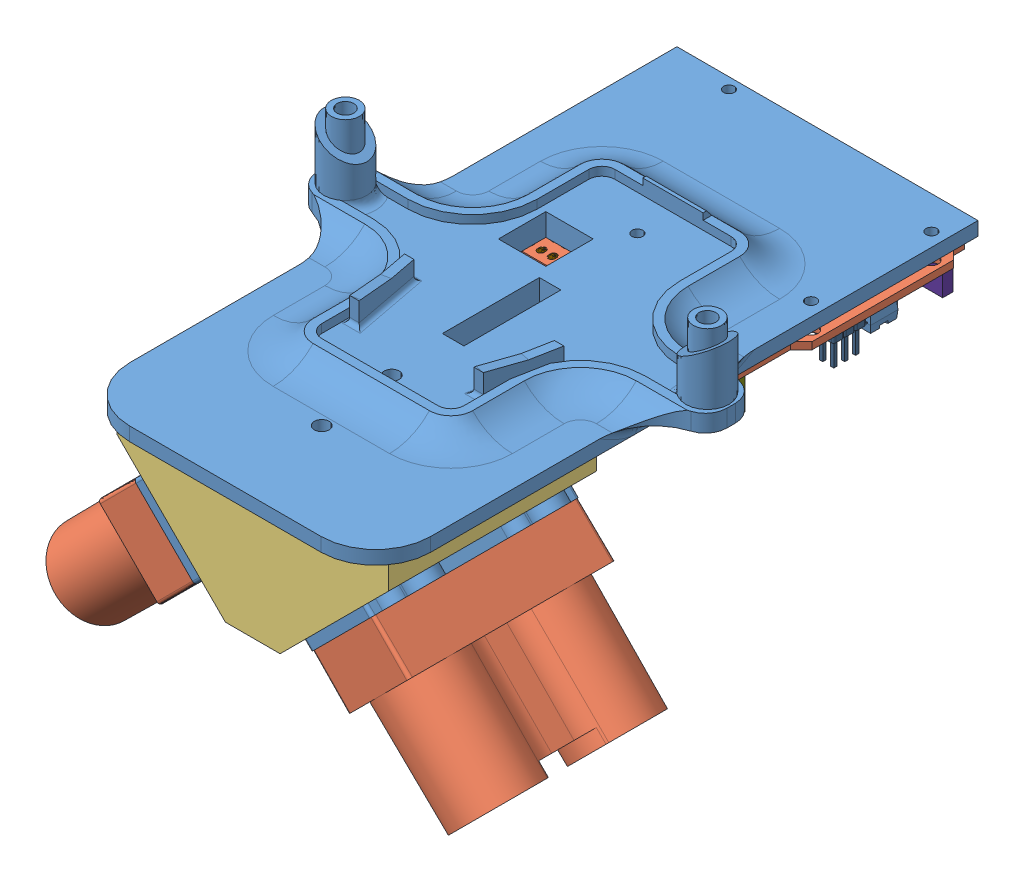
SolidWorks assembly Iris_LiDAR_Arduino_Mount, configuration Default. Lengths in mm.
Overall size (118.99 81.67 139.7).
94 component instances, 39 part files, 10 mates.
Components (placement in the parent):
- Iris_LiDAR_MountingPlate-1: Iris_LiDAR_MountingPlate [Default] x (1 0 0) z (0 1 0) size (95 139.7 22.9)
- arduino uno-1: arduino uno [Default] at (-34.29 -16.8811 -69.85) x (0 0 -1) z (-1 0 0) size (53.34 15.25 74.93)
  - unoboard blue-1: unoboard blue [Default] at origin size (53.34 1.65 68.58)
  - 47uf CAP Dcase-1: 47uf CAP Dcase [Default] at (-9.4141 0 -18.4991) x (0 0 -1) z (1 0 0) size (6.6 5.81 8)
  - USB SHELL-1: USB SHELL [Default] at (-38.02 0.43 6.35) size (13.72 15.2 16.51)
  - USB core-1: USB core [Default] at (-38.02 0.43 6.35) size (11.3 10.68 15.75)
  - usb top contact-1: usb top contact [Default] at (-36.77 6.52 5.97) size (1 9.67 13.76)
  - usb btm contact-1: usb btm contact [Default] at (-36.77 4.84 5.97) size (1 6.84 11.76)
  - usb btm contact-2: usb btm contact [Default] at (-39.27 4.84 5.97) size (1 6.84 11.76)
  - usb top contact-2: usb top contact [Default] at (-39.27 6.52 5.97) size (1 9.67 13.76)
  - power jack-1: power jack [Default] at (-7.675 0 1.905) size (11.2 15.2 15.9)
  - 47uf CAP Dcase-2: 47uf CAP Dcase [Default] at (-9.4141 0 -25.7132) x (0 0 -1) z (1 0 0) size (6.6 5.81 8)
  - crystal-1: crystal [Default] at (-26.162 0 -18.923) x (1 0 0) z (0 0 -1) size (4 5 11)
  - 2pin_header__02-1: 2pin_header__02 [Default] at (-46.23 0 -15.75) size (5 11.75 2.54)
  - nano - reg-1: nano - reg [Default] at (-17.399 0 -7.747) size (6.5 1.69 8.3)
  - led-1: led [Default] at (-34.29 0 -27.94) x (0 0 1) z (-1 0 0) size (4 0.9 1.55)
  - 2pin_header__02-2: 2pin_header__02 [Default] at (-30.43 0 -64.91) x (0 0 1) z (-1 0 0) size (5 11.75 2.54)
  - dip28-1: dip28 [Default] at (-16.383 1.5 -46.355) x (0 0 -1) z (1 0 0) size (35.48 2.8 10.1)
  - dip socket pin-1: dip socket pin [Default] at (-20.193 4.3 -62.865) x (0 0 -1) z (1 0 0) size (1.7 7.37 1.7)
  - dip socket pin-2: dip socket pin [Default] at (-12.573 4.3 -62.865) x (0 0 -1) z (1 0 0) size (1.7 7.37 1.7)
  - dip socket pin-3: dip socket pin [Default] at (-20.193 4.3 -60.325) x (0 0 -1) z (1 0 0) size (1.7 7.37 1.7)
  - dip socket pin-4: dip socket pin [Default] at (-12.573 4.3 -60.325) x (0 0 -1) z (1 0 0) size (1.7 7.37 1.7)
  - dip socket pin-5: dip socket pin [Default] at (-20.193 4.3 -57.785) x (0 0 -1) z (1 0 0) size (1.7 7.37 1.7)
  - dip socket pin-6: dip socket pin [Default] at (-12.573 4.3 -57.785) x (0 0 -1) z (1 0 0) size (1.7 7.37 1.7)
  - dip socket pin-7: dip socket pin [Default] at (-20.193 4.3 -55.245) x (0 0 -1) z (1 0 0) size (1.7 7.37 1.7)
  - dip socket pin-8: dip socket pin [Default] at (-12.573 4.3 -55.245) x (0 0 -1) z (1 0 0) size (1.7 7.37 1.7)
  - dip socket pin-9: dip socket pin [Default] at (-20.193 4.3 -52.705) x (0 0 -1) z (1 0 0) size (1.7 7.37 1.7)
  - dip socket pin-10: dip socket pin [Default] at (-12.573 4.3 -52.705) x (0 0 -1) z (1 0 0) size (1.7 7.37 1.7)
  - dip socket pin-11: dip socket pin [Default] at (-20.193 4.3 -50.165) x (0 0 -1) z (1 0 0) size (1.7 7.37 1.7)
  - dip socket pin-12: dip socket pin [Default] at (-12.573 4.3 -50.165) x (0 0 -1) z (1 0 0) size (1.7 7.37 1.7)
  - dip socket pin-13: dip socket pin [Default] at (-20.193 4.3 -47.625) x (0 0 -1) z (1 0 0) size (1.7 7.37 1.7)
  - dip socket pin-14: dip socket pin [Default] at (-12.573 4.3 -47.625) x (0 0 -1) z (1 0 0) size (1.7 7.37 1.7)
  - dip socket pin-15: dip socket pin [Default] at (-20.193 4.3 -45.085) x (0 0 -1) z (1 0 0) size (1.7 7.37 1.7)
  - dip socket pin-16: dip socket pin [Default] at (-12.573 4.3 -45.085) x (0 0 -1) z (1 0 0) size (1.7 7.37 1.7)
  - dip socket pin-17: dip socket pin [Default] at (-20.193 4.3 -42.545) x (0 0 -1) z (1 0 0) size (1.7 7.37 1.7)
  - dip socket pin-18: dip socket pin [Default] at (-12.573 4.3 -42.545) x (0 0 -1) z (1 0 0) size (1.7 7.37 1.7)
  - dip socket pin-19: dip socket pin [Default] at (-20.193 4.3 -40.005) x (0 0 -1) z (1 0 0) size (1.7 7.37 1.7)
  - dip socket pin-20: dip socket pin [Default] at (-12.573 4.3 -40.005) x (0 0 -1) z (1 0 0) size (1.7 7.37 1.7)
  - dip socket pin-21: dip socket pin [Default] at (-20.193 4.3 -37.465) x (0 0 -1) z (1 0 0) size (1.7 7.37 1.7)
  - dip socket pin-22: dip socket pin [Default] at (-12.573 4.3 -37.465) x (0 0 -1) z (1 0 0) size (1.7 7.37 1.7)
  - dip socket pin-23: dip socket pin [Default] at (-20.193 4.3 -34.925) x (0 0 -1) z (1 0 0) size (1.7 7.37 1.7)
  - dip socket pin-24: dip socket pin [Default] at (-12.573 4.3 -34.925) x (0 0 -1) z (1 0 0) size (1.7 7.37 1.7)
  - dip socket pin-25: dip socket pin [Default] at (-20.193 4.3 -32.385) x (0 0 -1) z (1 0 0) size (1.7 7.37 1.7)
  - dip socket pin-26: dip socket pin [Default] at (-12.573 4.3 -32.385) x (0 0 -1) z (1 0 0) size (1.7 7.37 1.7)
  - dip socket pin-27: dip socket pin [Default] at (-20.193 4.3 -29.845) x (0 0 -1) z (1 0 0) size (1.7 7.37 1.7)
  - dip socket pin-28: dip socket pin [Default] at (-12.573 4.3 -29.845) x (0 0 -1) z (1 0 0) size (1.7 7.37 1.7)
  - 2pin_header__02-3: 2pin_header__02 [Default] at (-27.89 0 -64.91) x (0 0 1) z (-1 0 0) size (5 11.75 2.54)
  - 2pin_header__02-4: 2pin_header__02 [Default] at (-25.35 0 -64.91) x (0 0 1) z (-1 0 0) size (5 11.75 2.54)
  - 2pin_header__02-5: 2pin_header__02 [Default] at (-46.23 0 -18.29) size (5 11.75 2.54)
  - 2pin_header__02-6: 2pin_header__02 [Default] at (-46.23 0 -20.83) size (5 11.75 2.54)
  - atmega16u2-1: atmega16u2 [Default] at (-34.671 0.06 -20) x (1 0 0) z (0 0 -1) size (5.5 1.01 5.5)
  - led-2: led [Default] at (-36.83 0 -27.94) x (0 0 1) z (-1 0 0) size (4 0.9 1.55)
  - led-3: led [Default] at (-42.037 0 -27.94) x (0 0 1) z (-1 0 0) size (4 0.9 1.55)
  - led-4: led [Default] at (-36.576 0 -58.42) x (0 0 1) z (-1 0 0) size (4 0.9 1.55)
  - 8 PORT HEADER-1: 8 PORT HEADER [Default] at (-50.8 0 -45.72) x (0 0 -1) z (1 0 0) size (20.32 10.51 2.41)
  - 8 PORT HEADER-2: 8 PORT HEADER [Default] at (-2.54 0 -27.94) x (0 0 -1) z (1 0 0) size (20.32 10.51 2.41)
  - 6 PORT HEADER-1: 6 PORT HEADER [Default] at (-2.54 0 -50.8) x (0 0 -1) z (1 0 0) size (15.24 10.51 2.41)
  - 10 PORT HEADER-1: 10 PORT HEADER [Default] at (-50.8 0 -18.796) x (0 0 -1) z (1 0 0) size (25.4 10.51 2.41)
  - ATMEL328P-1: ATMEL328P [Default] at (-16.383 4.3 -46.355) x (0 0 -1) z (1 0 0) size (35 7.27 7.87)
  - 102 RESISTOR PACK-1: 102 RESISTOR PACK [Default] at (-33.782 0 -58.42) size (3.2 0.51 3)
  - 102 RESISTOR PACK-2: 102 RESISTOR PACK [Default] at (-39.37 0 -27.94) size (3.2 0.51 3)
  - 103 RESISTOR PACK-1: 103 RESISTOR PACK [Default] at (-23.876 0 -27.94) size (3.2 0.51 3)
  - 220 RESISTOR PACK-1: 220 RESISTOR PACK [Default] at (-36.83 0 -12.827) size (3.2 0.51 3)
  - 16mhz crystal - measured-1: 16mhz crystal - measured [Default] at (-24.892 0 -41.275) x (0 0 -1) z (1 0 0) size (3.4 0.8 2)
  - PADS001-1: PADS001 [Default] at (-39.878 0.1 -18.288) x (-1 0 0) z (0 0 1) size (4.54 0.1 4.54)
  - 603 cap on pad-1: 603 cap on pad [Default] at (-44.45 0 -27.94) x (0 0 -1) z (1 0 0) size (2.76 0.91 1.02)
  - ssot3-1: ssot3 [Default] at (-26.5 0 -8.128) x (-1 0 0) z (0 0 -1) size (3 1.13 3.09)
  - mf-msmf050-2-1: mf-msmf050-2 [Default] at (-26.5 0 -4.064) size (5.76 1.02 3.72)
  - 603 cap on pad-2: 603 cap on pad [Default] at (-29.845 0 -27.94) x (0 0 -1) z (1 0 0) size (2.76 0.91 1.02)
  - 603 cap on pad-3: 603 cap on pad [Default] at (-31.496 0 -27.94) x (0 0 -1) z (1 0 0) size (2.76 0.91 1.02)
  - lmv358-1: lmv358 [Default] at (-15.24 0 -21.971) x (0 0 -1) z (1 0 0) size (3.7 1.4 2.9)
  - 603 cap on pad-4: 603 cap on pad [Default] at (-15.24 0 -18.415) size (2.76 0.91 1.02)
  - 603 cap on pad-5: 603 cap on pad [Default] at (-29.845 0 -12.065) x (0 0 1) z (-1 0 0) size (2.76 0.91 1.02)
  - 603 cap on pad-6: 603 cap on pad [Default] at (-29.591 0 -22.352) x (0 0 1) z (-1 0 0) size (2.76 0.91 1.02)
  - 603 cap on pad-7: 603 cap on pad [Default] at (-29.591 0 -16.002) x (0 0 1) z (-1 0 0) size (2.76 0.91 1.02)
  - 603 cap on pad-8: 603 cap on pad [Default] at (-41.91 0 -12.7) x (0 0 1) z (-1 0 0) size (2.76 0.91 1.02)
  - lp2985dgkr-1: lp2985dgkr [Default] at (-20.32 0 -19.05) x (0 0 -1) z (1 0 0) size (5.85 1.1 3)
  - cd1206 diode-1: cd1206 diode [Default] at (-27.94 0 -59.436) x (0 0 -1) z (1 0 0) size (2.09 0.96 5)
  - cd1206 diode-2: cd1206 diode [Default] at (-46.228 0 -13.081) x (0 0 1) z (-1 0 0) size (2.09 0.96 5)
  - 603 resistor-1: 603 resistor [Default] at (-29.591 0 -19.05) x (0 0 1) z (-1 0 0) size (2.36 0.62 1.03)
  - blm21-1: blm21 [Default] at (-45.085 0 -7.62) x (0 0 -1) z (1 0 0) size (2.78 0.95 1.32)
  - m7 diode-1: m7 diode [Default] at (-2.794 0 -21.59) x (0 0 -1) z (1 0 0) size (6.66 2.35 2.5)
  - MLC0603-1: MLC0603 [Default] at (-33.655 0 -12.827) x (0 0 -1) z (1 0 0) size (2.36 0.6 1.03)
  - MLC0603-2: MLC0603 [Default] at (-39.37 0 -12.827) x (0 0 -1) z (1 0 0) size (2.36 0.6 1.03)
  - RESET CORE-1: RESET CORE [Default] at (-49.403 0.1 -6.35) x (-1 0 0) z (0 0 -1) size (6.2 3.1 9.6)
  - RESET-1: RESET [Default] at (-49.403 0.1 -6.35) x (0 0 1) z (-1 0 0) size (7.3 2 6.2)
- 2_Lidars-1: 2_Lidars [Default] at (38.1 -38.3326 39.346) x (0 0 1) z (-1 0 0) size (48.26 59.5 118.99)
  - LiDAR_Lite-1: LiDAR_Lite [Default] at (-28.1042 -5.9237 32.1958) x (1 0 0) z (0 0.707107 -0.707107) size (48.26 39.85 35.56)
    - LIDAR-Lite_Base-1: LIDAR-Lite_Base [Default] at (3.9982 4.445 0.3764) x (1 0 0) z (0 -1 0) size (48.26 35.56 5.72)
    - LIDAR-Lite_Housing_RevD-1: LIDAR-Lite_Housing_RevD [Default] at (52.0437 2.54 8.1475) x (-1 0 0) z (0 1 0) size (47.88 20.07 37.31)
  - LiDAR_Lite-3: LiDAR_Lite [Default] at (28.1523 -5.9237 44.0042) x (-1 0 0) z (0 0.707107 0.707107) size (48.26 39.85 35.56)
    - LIDAR-Lite_Base-1: LIDAR-Lite_Base [Default] at (3.9982 4.445 0.3764) x (1 0 0) z (0 -1 0) size (48.26 35.56 5.72)
    - LIDAR-Lite_Housing_RevD-1: LIDAR-Lite_Housing_RevD [Default] at (52.0437 2.54 8.1475) x (-1 0 0) z (0 1 0) size (47.88 20.07 37.31)
  - 45Block^2_Lidars-1: 45Block^2_Lidars [Default] at (0 25.4 0) x (1 0 0) z (0 1 0) size (48.26 62.99 31.49) (virtual)
Mates (geometry in assembly coordinates):
- Coincident1: coincident anti-aligned: plane of Iris_LiDAR_MountingPlate-1 through (0 0 0) normal (0 0 -1); plane of assembly through (0 0 0) normal (0 0 1)
- Coincident2: coincident aligned: plane of Iris_LiDAR_MountingPlate-1 through (0 0 0) normal (0 1 0); plane of assembly through (0 0 0) normal (0 1 0)
- Coincident3: coincident aligned: plane of Iris_LiDAR_MountingPlate-1; plane of assembly through (0 0 0) normal (1 0 0)
- Parallel1: parallel aligned: plane of Iris_LiDAR_MountingPlate-1 through (0 -12.675 0) normal (0 -1 0); plane of arduino uno-1/unoboard blue-1
- Parallel2: parallel anti-aligned: plane of arduino uno-1/unoboard blue-1; plane of assembly through (0 0 0) normal (0 0 1)
- Coincident7: coincident aligned: plane of arduino uno-1/unoboard blue-1 through (0 -16.8811 -69.85) normal (1 0 0); plane of assembly through (0 0 0) normal (1 0 0)
- Coincident9: coincident aligned: plane of Iris_LiDAR_MountingPlate-1 through (34.925 -12.675 -69.85) normal (0 0 -1); plane of arduino uno-1/unoboard blue-1 through (-34.29 -15.2311 -69.85) normal (0 0 -1)
- Coincident34: coincident anti-aligned: plane of Iris_LiDAR_MountingPlate-1 through (0 -12.675 0) normal (0 -1 0); plane of 2_Lidars-1/45Block^2_Lidars-1 through (31.4947 -12.675 133.9243) normal (0 1 0)
- Distance6: distance = 6.35 mm aligned: plane of Iris_LiDAR_MountingPlate-1 through (34.925 -12.675 69.85) normal (0 0 1); plane of 2_Lidars-1/45Block^2_Lidars-1 through (-6.1704 -43.9901 63.5) normal (0 0 1)
- Symmetric1: symmetric aligned: plane of Iris_LiDAR_MountingPlate-1 through (-34.925 -12.675 -69.85) normal (-1 0 0); plane of Iris_LiDAR_MountingPlate-1 through (34.925 -12.675 -69.85) normal (1 0 0); plane of 2_Lidars-1 through (0 -38.3326 39.346) normal (-1 0 0)
